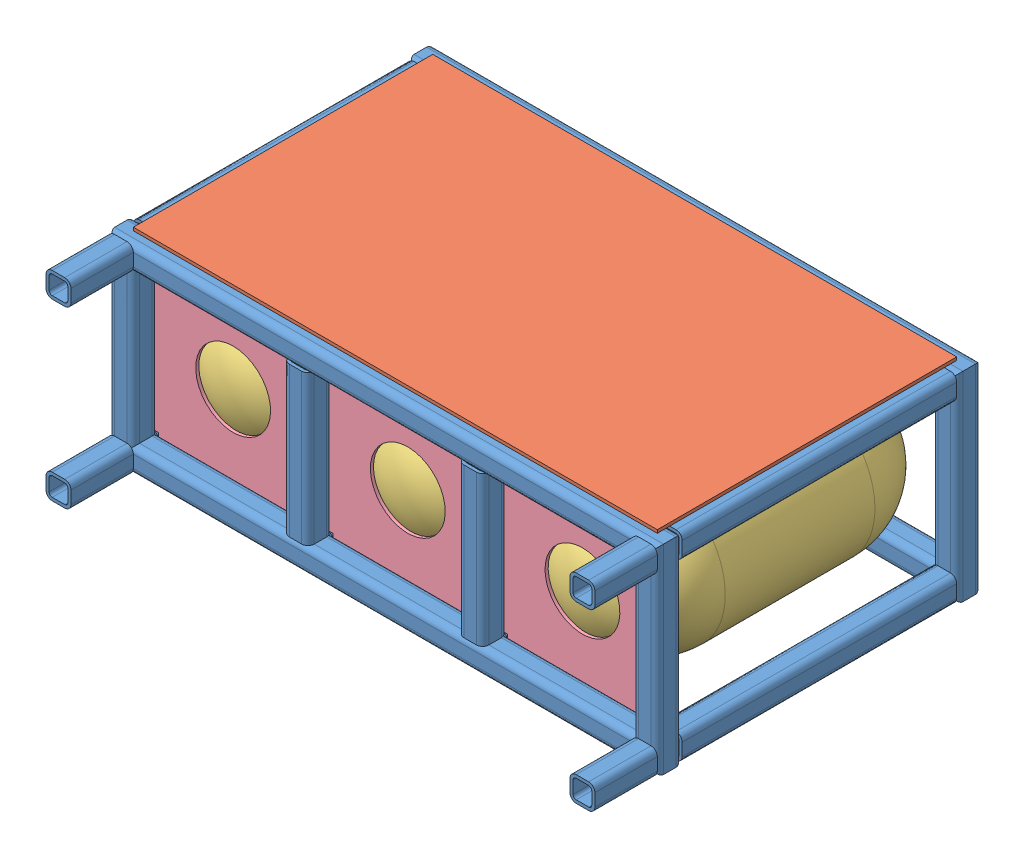
SolidWorks assembly tank stand assembly 1.0, configuration Default. Lengths in mm.
Overall size (1117.6 412.75 787.4).
8 component instances, 4 part files, 18 mates.
Components (placement in the parent):
- tank stand frame 1.0-1: tank stand frame 1.0 [Default<As Machined>] at origin size (1117.6 406.4 787.4)
- main mounting plate 1.0-1: main mounting plate 1.0 [Default] at (0 31.75 -609.6) x (1 0 0) z (0 -1 0) size (1066.8 609.6 6.35)
- propellant tank 1.0-1: propellant tank 1.0 [Default] at (-177.8 -177.8 -11.3323) x (0.99335 -0.115135 0) z (-0.115135 -0.99335 0) size (304.8 609.6 304.8)
- propellant tank 1.0-2: propellant tank 1.0 [Default] at (-533.4 -177.8 -11.3323) x (0.998796 -0.049052 0) z (-0.049052 -0.998796 0) size (304.8 609.6 304.8)
- propellant tank 1.0-3: propellant tank 1.0 [Default] at (-889 -177.8 -11.3323) x (0.963104 0.269129 0) z (0.269129 -0.963104 0) size (304.8 609.6 304.8)
- lower tank mount 1.0-1: lower tank mount 1.0 [Default] at (-736.6 -330.2 -31.75) x (1 0 0) z (0 -1 0) size (355.6 6.35 355.6)
- lower tank mount 1.0-2: lower tank mount 1.0 [Default] at (-381 -330.2 -31.75) x (1 0 0) z (0 -1 0) size (355.6 6.35 355.6)
- lower tank mount 1.0-3: lower tank mount 1.0 [Default] at (-25.4 -330.2 -31.75) x (1 0 0) z (0 -1 0) size (355.6 6.35 355.6)
Mates (geometry in assembly coordinates):
- Coincident1: coordinate: point of tank stand frame 1.0-1
- Coincident2: coincident anti-aligned: plane of tank stand frame 1.0-1 through (-1066.8 25.4 -622.3) normal (0 1 0); plane of main mounting plate 1.0-1 through (0 25.4 -609.6) normal (0 -1 0)
- Coincident3: coincident anti-aligned: line of tank stand frame 1.0-1 through (-1066.8 0 -609.6) axis (0 -1 0); line of main mounting plate 1.0-1 through (-1066.8 25.4 -609.6) axis (0 1 0)
- Coincident4: coincident anti-aligned: plane of tank stand frame 1.0-1 through (0 -368.3 -25.4) normal (0 0 -1); plane of lower tank mount 1.0-1 through (-736.6 -330.2 -25.4) normal (0 0 1)
- Coincident5: coincident anti-aligned: plane of tank stand frame 1.0-1 through (-736.6 -368.3 0) normal (-1 0 0); plane of lower tank mount 1.0-1 through (-736.6 -330.2 -25.4) normal (1 0 0)
- Coincident6: coincident anti-aligned: plane of tank stand frame 1.0-1 through (-698.5 -330.2 0) normal (0 1 0); plane of lower tank mount 1.0-1 through (-711.2 -330.2 -25.4) normal (0 -1 0)
- Coincident7: coincident anti-aligned: plane of tank stand frame 1.0-1 through (0 -368.3 -25.4) normal (0 0 -1); plane of lower tank mount 1.0-2 through (-381 -330.2 -25.4) normal (0 0 1)
- Coincident8: coincident anti-aligned: plane of tank stand frame 1.0-1 through (-381 -368.3 0) normal (-1 0 0); plane of lower tank mount 1.0-2 through (-381 -330.2 -25.4) normal (1 0 0)
- Coincident9: coincident anti-aligned: plane of tank stand frame 1.0-1 through (-342.9 -330.2 0) normal (0 1 0); plane of lower tank mount 1.0-2 through (-355.6 -330.2 -25.4) normal (0 -1 0)
- Coincident10: coincident anti-aligned: plane of tank stand frame 1.0-1 through (12.7 0 -25.4) normal (0 0 -1); plane of lower tank mount 1.0-3 through (-25.4 -330.2 -25.4) normal (0 0 1)
- Coincident11: coincident anti-aligned: plane of tank stand frame 1.0-1 through (12.7 -330.2 0) normal (0 1 0); plane of lower tank mount 1.0-3 through (0 -330.2 -25.4) normal (0 -1 0)
- Coincident12: coincident: line of tank stand frame 1.0-1 through (-25.4 -368.3 -25.4) axis (0 0 -1); plane of lower tank mount 1.0-3 through (-25.4 -330.2 -25.4) normal (1 0 0)
- Concentric1: concentric: cylinder of propellant tank 1.0-3 through (-889 -177.8 -620.9323) axis (0 0 -1) radius 152.4; cylinder of lower tank mount 1.0-1 through (-889 -177.8 -25.4) axis (0 0 -1) radius 76.2
- Concentric2: concentric: cylinder of propellant tank 1.0-2 through (-533.4 -177.8 -620.9323) axis (0 0 -1) radius 152.4; cylinder of lower tank mount 1.0-2 through (-533.4 -177.8 -25.4) axis (0 0 -1) radius 76.2
- Concentric3: concentric aligned: cylinder of propellant tank 1.0-1 through (-177.8 -177.8 -620.9323) axis (0 0 -1) radius 152.4; cylinder of lower tank mount 1.0-3 through (-177.8 -177.8 -25.4) axis (0 0 -1) radius 76.2
- Tangent5: tangent: sphere of propellant tank 1.0-1; circle of lower tank mount 1.0-3
- Tangent6: tangent: sphere of propellant tank 1.0-2; circle of lower tank mount 1.0-2
- Tangent7: tangent: sphere of propellant tank 1.0-3; circle of lower tank mount 1.0-1
